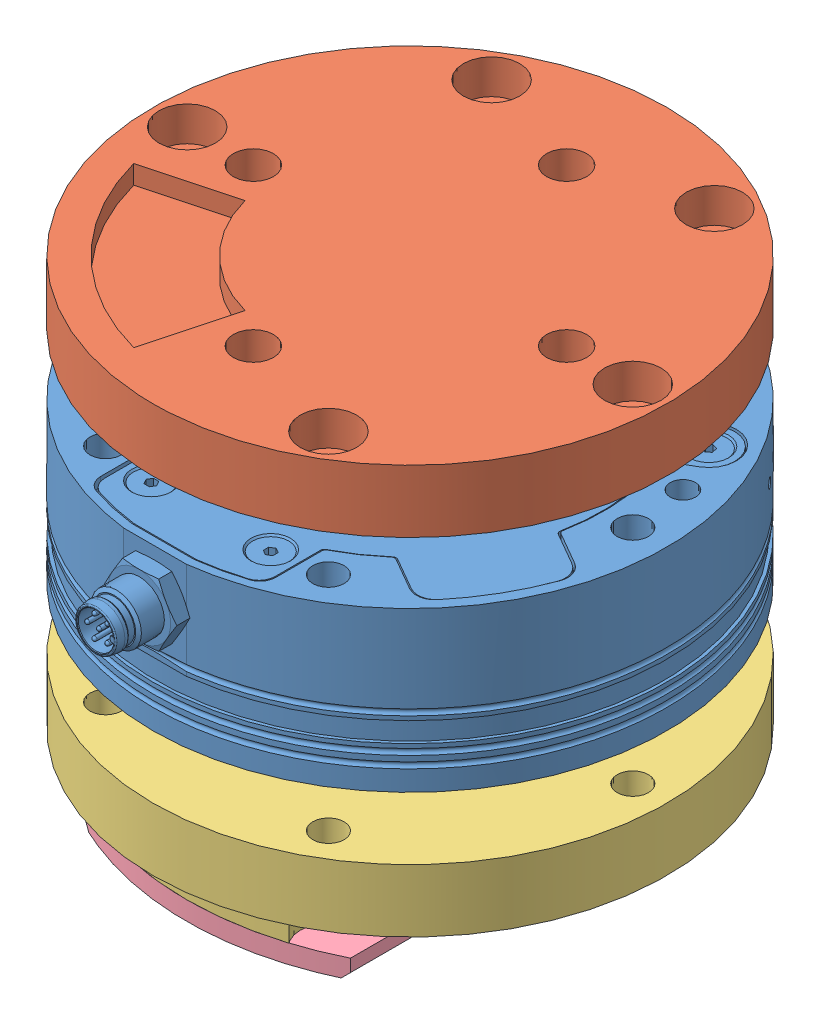
SolidWorks assembly adaptor assem, configuration Default. Lengths in mm.
Overall size (82 74.38 91.2).
4 component instances, 4 part files, 10 mates.
Components (placement in the parent):
- ATI-9105-Axia80-M8-2: ATI-9105-Axia80-M8 [Default] at origin size (82 25.4 91.2)
- Panda Robot Adaptor Plate-1: Panda Robot Adaptor Plate [Default] at (0 26.7765 -43.194) x (-1 0 0) z (0 0 1) size (82 10 82)
- Right Hand Adaptor Part 2-1: Right Hand Adaptor Part 2 [Default] at (0 -38.433 -41.044) x (-1 0 0) z (0 0 1) size (82 19.18 82)
- Right Hand Adaptor Part 1-1: Right Hand Adaptor Part 1 [Default] at (0 -44.433 -41.044) x (-1 0 0) z (0 0 1) size (42.3 3 70.35)
Mates (geometry in assembly coordinates):
- Parallel1: parallel anti-aligned: plane of ATI-9105-Axia80-M8-2 through (0 6.7765 -43.194) normal (0 1 0); plane of Panda Robot Adaptor Plate-1 through (0 16.7765 -43.194) normal (0 -1 0)
- Concentric1: concentric anti-aligned: cylinder of ATI-9105-Axia80-M8-2 through (0 6.967 -43.194) axis (0 -1 0) radius 41; cylinder of Panda Robot Adaptor Plate-1 through (0 16.7765 -43.194) axis (0 1 0) radius 41
- Coincident1: coincident anti-aligned: plane of Right Hand Adaptor Part 2-1 through (0 -44.433 -41.044) normal (0 -1 0); plane of Right Hand Adaptor Part 1-1 through (0 -44.433 -41.044) normal (0 1 0)
- Coincident2: coincident anti-aligned: plane of Right Hand Adaptor Part 2-1 through (7.375 -47.608 -58.344) normal (1 0 0); plane of Right Hand Adaptor Part 1-1 through (7.375 -15.1473 -58.344) normal (-1 0 0)
- Concentric2: concentric anti-aligned: cylinder of Right Hand Adaptor Part 2-1 through (0 -47.608 -61.6097) axis (0 1 0) radius 8.0657; cylinder of Right Hand Adaptor Part 1-1 through (0 -15.1473 -61.6097) axis (0 -1 0) radius 8.0657
- Coincident3: coincident anti-aligned: plane of Panda Robot Adaptor Plate-1 through (0 26.7765 -43.194) normal (-1 0 0)
- Coincident4: coincident anti-aligned: plane of Right Hand Adaptor Part 2-1 through (0 -38.433 -41.044) normal (-1 0 0)
- Distance1: distance = 10 mm anti-aligned: plane of Panda Robot Adaptor Plate-1 through (0 16.7765 -43.194) normal (0 -1 0); plane of ATI-9105-Axia80-M8-2 through (0 6.7765 -43.194) normal (0 1 0)
- Concentric6: concentric aligned: cylinder of ATI-9105-Axia80-M8-2 through (0 6.967 -43.194) axis (0 -1 0) radius 41; cylinder of Right Hand Adaptor Part 2-1 through (0 -28.433 -43.194) axis (0 -1 0) radius 41
- Distance3: distance = 10 mm anti-aligned: plane of ATI-9105-Axia80-M8-2 through (0 -18.433 -43.194) normal (0 -1 0); plane of Right Hand Adaptor Part 2-1 through (0 -28.433 -43.194) normal (0 1 0)
